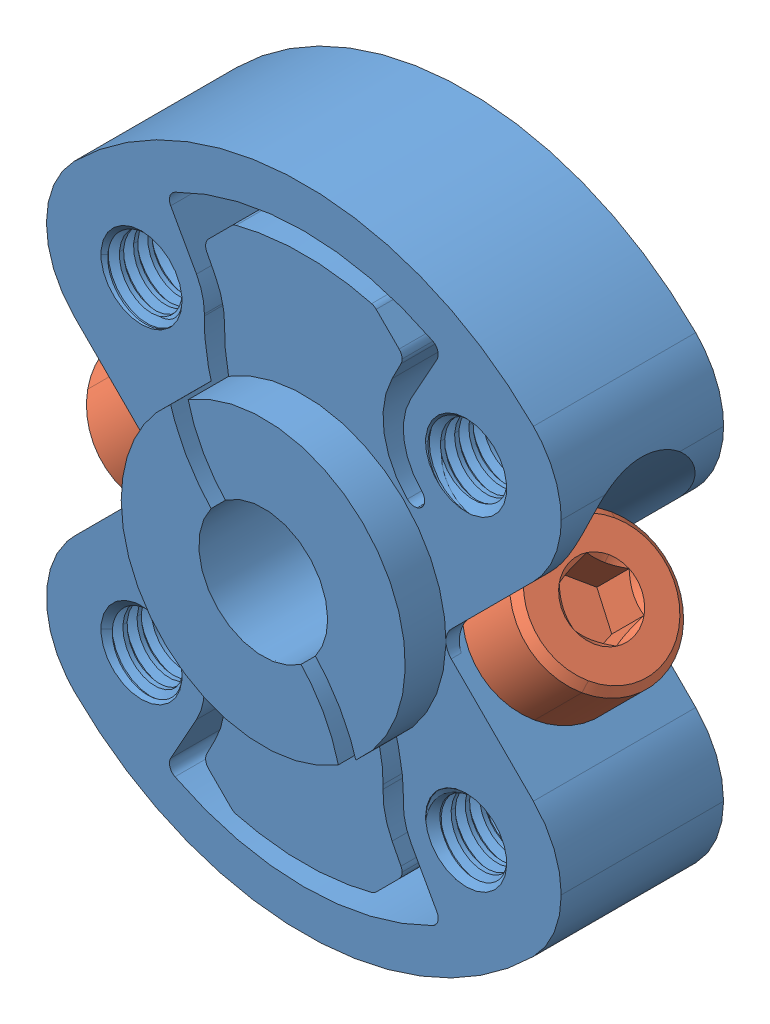
SolidWorks assembly 0.25 inch Hub 1309-0016-0250, configuration Default. Lengths in mm.
Overall size (28.36 32 10.95).
3 component instances, 2 part files, 0 mates.
Components (placement in the parent):
- 1309-0016-0250.STEP-1: 1309-0016-0250.STEP [Default] at (-10.6543 7.2087 0.2858) size (25.38 32 10)
- 2800-0004-0014_90128A207.STEP-1: 2800-0004-0014_90128A207.STEP [Default] at (-12.7071 -3.91 0.2858) x (0.5 -0.5 0.707107) z (-0.707107 -0.707107 0) size (7 7 18.01)
- 2800-0004-0014_90128A207.STEP-2: 2800-0004-0014_90128A207.STEP [Default] at (-8.6014 18.3274 0.2858) x (-0.5 0.5 0.707107) z (0.707107 0.707107 0) size (7 7 18.01)
